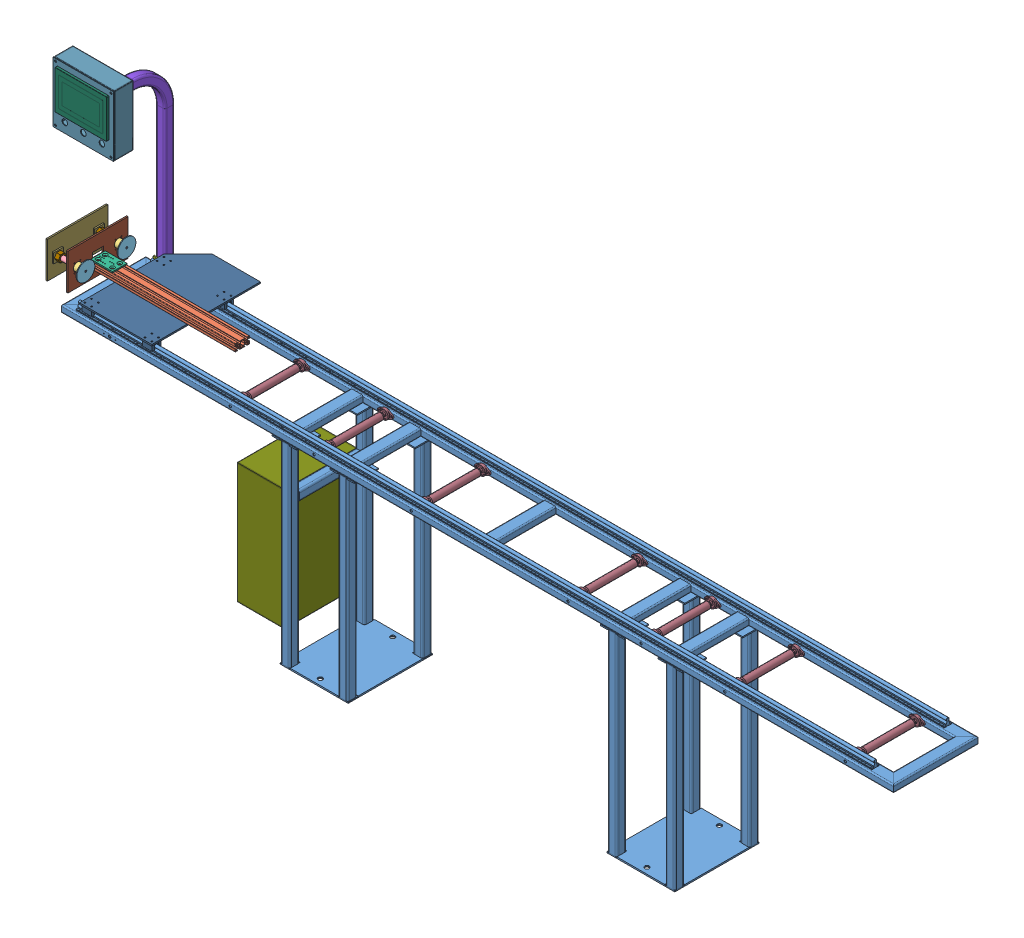
SolidWorks assembly machine-on, configuration Default. Lengths in mm.
Overall size (3563.76 1673.42 450).
29 component instances, 17 part files, 80 mates.
Components (placement in the parent):
- khung-1: khung [Default<As Machined>] at (964.4344 1502.6729 3549.2944) x (-1 0 0) z (0 0 1) size (3450 866.5 350)
- aluminium3060-600-1: aluminium3060-600 [Default<As Machined>] at (-185.5656 1577.1729 3549.2944) x (1 0 0) z (0 -1 0) size (600 60 30)
- LMH20UUx42-1: LMH20UUx42 [Default] at (-776.5656 1597.8953 3634.2944) size (42 54 38)
- LMH20UUx42-2: LMH20UUx42 [Default] at (-776.5656 1597.8953 3464.2944) size (42 54 38)
- truc)x-2: truc)x [Default] at (-752.3281 1597.8953 3634.2944) x (0 0.993547 -0.113425) z (0 0.113425 0.993547) size (20.5 122 21.25)
- chan3-1: chan3 [Default] at (-749.3281 1597.8953 3634.2944) x (0 0.828554 -0.559909) z (0 0.559909 0.828554) size (75 3 75)
- ga_bat-xilanhx80-1: ga_bat-xilanhx80 [Default] at (-738.5656 1592.1729 3549.2944) x (0 0 -1) z (1 0 0) size (60 5 90)
- v-50100-1: v-50100 [Default] at (-730.5656 1487.6729 3424.2944) x (0 0 -1) z (0 -1 0) size (55 100 50)
- gia-display-1: gia-display [Default<As Machined>] at (-705.5656 1428.6729 3349.2944) x (0 0 1) z (0 -1 0) size (276.08 230 916)
- v-50100-2: v-50100 [Default] at (-630.5656 1532.6729 3364.2944) x (-1 0 0) z (0 0 1) size (55 100 50)
- hex nut gradec_iso-1: hex nut gradec_iso [ISO - 4034 - M20 - N] at (-864.3281 1597.8953 3464.2944) x (0 -0.820442 -0.57173) z (-1 0 0) size (30 34.64 19)
- hex nut gradec_iso-2: hex nut gradec_iso [ISO - 4034 - M20 - N] at (-864.3281 1597.8953 3634.2944) x (0 1 0) z (-1 0 0) size (30 34.64 19)
- layout-table-2: layout-table [Default] at (-535.5656 1556.1729 3549.2944) size (300 31.9 450)
- chan_ban-2: chan_ban [Default] at (-789.5656 1597.6729 3549.2944) x (0 0 -1) z (0 -1 0) size (250 6 150)
- chan3-3: chan3 [Default] at (-749.3281 1597.8953 3464.2944) x (0 -0.419054 -0.907961) z (0 0.907961 -0.419054) size (75 3 75)
- truc)x-3: truc)x [Default] at (-752.3281 1597.8953 3464.2944) x (0 0.92615 0.377155) z (0 -0.377155 0.92615) size (20.5 122 21.25)
- chan2-2: chan2 [Default] at (-874.3281 1598.1153 3549.2944) x (0 0 1) z (0 1 0) size (250 12 150)
- pvc 200-2: pvc 200 [Default] at (-560.5656 1502.6729 3649.2944) x (0.546944 0.837169 0) z (-0.837169 0.546944 0) size (41.25 250 55.18)
- pvc 200-3: pvc 200 [Default] at (-60.5656 1502.6729 3449.2944) x (-0.546944 0.837169 0) z (0.837169 0.546944 0) size (41.25 250 55.18)
- pvc 200-4: pvc 200 [Default] at (286.4344 1502.6729 3449.2944) x (-0.546944 0.837169 0) z (0.837169 0.546944 0) size (41.25 250 55.18)
- pvc 200-5: pvc 200 [Default] at (689.4344 1502.6729 3449.2944) x (-0.546944 0.837169 0) z (0.837169 0.546944 0) size (41.25 250 55.18)
- pvc 200-6: pvc 200 [Default] at (1339.4344 1502.6729 3449.2944) x (-0.546944 0.837169 0) z (0.837169 0.546944 0) size (41.25 250 55.18)
- pvc 200-7: pvc 200 [Default] at (1642.4344 1502.6729 3449.2944) x (-0.546944 0.837169 0) z (0.837169 0.546944 0) size (41.25 250 55.18)
- pvc 200-8: pvc 200 [Default] at (1989.4344 1502.6729 3449.2944) x (0.546944 -0.837169 0) z (-0.837169 -0.546944 0) size (41.25 250 55.18)
- pvc 200-9: pvc 200 [Default] at (2489.4344 1502.6729 3449.2944) x (0.546944 -0.837169 0) z (-0.837169 -0.546944 0) size (41.25 250 55.18)
- Part2-1: Part2 [Default] at (-705.5656 2228.6729 3608.2944) x (0 -1 0) z (0 0 1) size (250.85 250.82 83.42)
- Delta DOP-107BV HMI-1: Delta DOP-107BV HMI [Varsayılan] at (-707.4156 2249.8229 3697.7944) x (1 0 0) z (0 0 -1) size (215 160.7 36.74)
- table electrical-1: table electrical [Default] at (143.4344 1045.6729 3554.2944) x (0 0 -1) z (0 1 0) size (300.76 200.75 500.76)
- door_table-1: door_table [Default] at (-50.0656 1046.1729 3553.0015) x (0 0 1) z (0 -1 0) size (237.66 7.33 448)
Mates (geometry in assembly coordinates):
- Coincident21: coincident aligned: circle of LMH20UUx42-1; cylinder of truc)x-2 through (-872.3544 1597.8953 3634.2944) axis (1 0 0) radius 10
- Coincident23: coincident anti-aligned: plane of truc)x-2 through (-750.3544 1597.8953 3634.2944) normal (1 0 0); plane of chan3-1 through (-750.3544 1597.8953 3634.2944) normal (-1 0 0)
- Concentric18: concentric anti-aligned: circle of truc)x-2; circle of chan3-1
- Coincident28: coincident anti-aligned: plane of aluminium3060-600-1 through (-785.5656 1592.1729 3559.9944) normal (0 1 0); plane of ga_bat-xilanhx80-1 through (-738.5656 1592.1729 3549.2944) normal (0 -1 0)
- Coincident29: coincident aligned: plane of aluminium3060-600-1 through (-785.5656 1590.1729 3519.2944) normal (0 0 -1); plane of ga_bat-xilanhx80-1 through (-738.5656 1597.1729 3519.2944) normal (0 0 -1)
- Coincident34: coincident anti-aligned: plane of khung-1 through (-735.5656 1487.6729 3419.0944) normal (0 -1 0); plane of v-50100-1 through (-630.5656 1487.6729 3424.2944) normal (0 1 0)
- Coincident35: coincident anti-aligned: plane of khung-1 through (-735.5656 1512.4729 3374.2944) normal (0 0 -1); plane of v-50100-1 through (-630.5656 1487.6729 3374.2944) normal (0 0 1)
- Distance4: distance = 30 mm aligned: plane of khung-1 through (-760.5656 1512.4729 3699.2944) normal (-1 0 0); plane of v-50100-1 through (-730.5656 1487.6729 3424.2944) normal (-1 0 0)
- Coincident37: coincident anti-aligned: plane of v-50100-1 through (-630.5656 1532.6729 3369.2944) normal (0 0 -1); plane of gia-display-1 through (-693.5656 2078.6729 3369.2944) normal (0 0 1)
- Distance6: distance = 60 mm aligned: plane of khung-1 through (-735.5656 1487.6729 3419.0944) normal (0 -1 0); plane of gia-display-1 through (-717.0656 1427.6729 3360.8754) normal (0 -1 0)
- Distance5: distance = 5 mm aligned: plane of gia-display-1 through (-725.5656 2078.6729 3337.2944) normal (-1 0 0); plane of v-50100-1 through (-730.5656 1487.6729 3424.2944) normal (-1 0 0)
- Coincident40: coincident anti-aligned: plane of gia-display-1 through (-685.5656 2078.6729 3361.2944) normal (1 0 0); plane of v-50100-2 through (-685.5656 1432.6729 3319.2944) normal (-1 0 0)
- Coincident42: coincident anti-aligned: plane of v-50100-1 through (-630.5656 1532.6729 3369.2944) normal (0 0 -1); plane of v-50100-2 through (-685.5656 1432.6729 3369.2944) normal (0 0 1)
- Coincident43: coincident aligned: plane of v-50100-1 through (-630.5656 1532.6729 3374.2944) normal (0 1 0); plane of v-50100-2 through (-630.5656 1532.6729 3364.2944) normal (0 1 0)
- Concentric22: concentric anti-aligned: cylinder of truc)x-2 through (-872.3544 1597.8953 3634.2944) axis (1 0 0) radius 10; cylinder of hex nut gradec_iso-2 through (-843.3544 1597.8953 3634.2944) axis (-1 0 0) radius 8.75
- Concentric23: concentric anti-aligned: cylinder of khung-1 through (2589.4344 1541.1729 3699.2944) axis (-1 0 0) radius 6; cylinder of layout-table-2 through (-678.0656 1541.1729 3699.2944) axis (1 0 0) radius 6
- Parallel4: parallel anti-aligned: plane of khung-1 through (-755.3656 1517.6729 3699.2944) normal (0 1 0); plane of layout-table-2 through (-535.5656 1556.1729 3549.2944) normal (0 -1 0)
- Coincident44: coincident anti-aligned: plane of aluminium3060-600-1 through (-785.5656 1562.1729 3538.5944) normal (0 -1 0); plane of layout-table-2 through (-535.5656 1562.1729 3549.2944) normal (0 1 0)
- Distance7: distance = 145 mm aligned: plane of aluminium3060-600-1 through (-785.5656 1564.1729 3579.2944) normal (0 0 1); plane of layout-table-2 through (-535.5656 1562.1729 3724.2944) normal (0 0 1)
- Distance8: distance = 200 mm aligned: plane of layout-table-2 through (-385.5656 1562.1729 3549.2944) normal (1 0 0); plane of aluminium3060-600-1 through (-185.5656 1590.1729 3521.2944) normal (1 0 0)
- Coincident47: coincident anti-aligned: plane of aluminium3060-600-1 through (-785.5656 1590.1729 3521.2944) normal (-1 0 0); plane of chan_ban-2 through (-785.5656 1597.6729 3549.2944) normal (1 0 0)
- Concentric24: concentric anti-aligned: circle of aluminium3060-600-1; circle of chan_ban-2
- Coincident49: coincident anti-aligned: plane of ga_bat-xilanhx80-1 through (-783.5656 1597.1729 3549.2944) normal (-1 0 0); plane of chan_ban-2 through (-783.5656 1597.6729 3549.2944) normal (1 0 0)
- Concentric25: concentric anti-aligned: cylinder of LMH20UUx42-1 through (-826.5656 1597.8953 3634.2944) axis (-1 0 0) radius 16; cylinder of chan_ban-2 through (-812.5656 1597.8953 3634.2944) axis (1 0 0) radius 17
- Coincident50: coincident anti-aligned: plane of LMH20UUx42-1 through (-789.5656 1597.8953 3634.2944) normal (1 0 0); plane of chan_ban-2 through (-789.5656 1597.6729 3549.2944) normal (-1 0 0)
- Parallel5: parallel aligned: plane of LMH20UUx42-1 through (-789.5656 1617.0786 3653.2944) normal (0 0 1); plane of chan_ban-2 through (-783.5656 1597.6729 3674.2944) normal (0 0 1)
- Concentric26: concentric anti-aligned: cylinder of LMH20UUx42-2 through (-826.5656 1597.8953 3464.2944) axis (-1 0 0) radius 16; cylinder of chan_ban-2 through (-812.5656 1597.8953 3464.2944) axis (1 0 0) radius 17
- Parallel6: parallel anti-aligned: plane of LMH20UUx42-2 through (-789.5656 1617.0786 3483.2944) normal (0 0 1); plane of chan_ban-2 through (-783.5656 1597.6729 3424.2944) normal (0 0 -1)
- Coincident53: coincident anti-aligned: plane of LMH20UUx42-2 through (-789.5656 1597.8953 3464.2944) normal (1 0 0); plane of chan_ban-2 through (-789.5656 1597.6729 3549.2944) normal (-1 0 0)
- Parallel7: parallel aligned: plane of aluminium3060-600-1 through (-785.5656 1592.1729 3529.9944) normal (0 1 0); plane of chan_ban-2 through (-783.5656 1672.6729 3549.2944) normal (0 1 0)
- LimitDistance1: limit distance = 50 mm anti-aligned: plane of LMH20UUx42-1 through (-755.5656 1612.8453 3634.2944) normal (1 0 0); plane of chan3-1 through (-752.3281 1597.8953 3634.2944) normal (-1 0 0)
- Concentric27: concentric anti-aligned: circle of chan3-3; circle of truc)x-3
- Coincident56: coincident anti-aligned: plane of chan3-3 through (-750.3544 1597.8953 3464.2944) normal (-1 0 0); plane of truc)x-3 through (-750.3544 1597.8953 3464.2944) normal (1 0 0)
- Concentric28: concentric aligned: cylinder of LMH20UUx42-2 through (-797.5656 1597.8953 3464.2944) axis (1 0 0) radius 10; cylinder of truc)x-3 through (-872.3544 1597.8953 3464.2944) axis (1 0 0) radius 10
- LimitDistance3: limit distance = 50 mm anti-aligned: plane of chan3-3 through (-752.3281 1597.8953 3464.2944) normal (-1 0 0); plane of LMH20UUx42-2 through (-755.5656 1612.8453 3464.2944) normal (1 0 0)
- Coincident58: coincident aligned: plane of chan3-1 through (-747.3544 1597.8953 3634.2944) normal (1 0 0); plane of chan3-3 through (-747.3544 1597.8953 3464.2944) normal (1 0 0)
- LimitDistance4: limit distance = 0 mm anti-aligned: plane of layout-table-2 through (-685.5656 1562.1729 3549.2944) normal (-1 0 0); plane of gia-display-1 through (-685.5656 2078.6729 3361.2944) normal (1 0 0)
- Concentric29: concentric anti-aligned: cylinder of hex nut gradec_iso-1 through (-843.3544 1597.8953 3464.2944) axis (-1 0 0) radius 8.75; cylinder of truc)x-3 through (-872.3544 1597.8953 3464.2944) axis (1 0 0) radius 10
- Distance14: distance = 10 mm aligned: plane of hex nut gradec_iso-1 through (-864.3281 1587.9926 3478.5049) normal (-1 0 0); plane of truc)x-3 through (-874.3281 1597.8953 3464.2944) normal (-1 0 0)
- Concentric30: concentric anti-aligned: cylinder of truc)x-2 through (-872.3544 1597.8953 3634.2944) axis (1 0 0) radius 10; cylinder of hex nut gradec_iso-2 through (-843.3544 1597.8953 3634.2944) axis (-1 0 0) radius 8.75
- Coincident63: coincident aligned: plane of hex nut gradec_iso-1 through (-862.3544 1587.9926 3478.5049) normal (-1 0 0); plane of hex nut gradec_iso-2 through (-862.3544 1597.8953 3616.9739) normal (-1 0 0)
- Concentric31: concentric anti-aligned: cylinder of truc)x-3 through (-872.3544 1597.8953 3464.2944) axis (1 0 0) radius 10; cylinder of chan2-2 through (-860.3544 1597.8953 3464.2944) axis (-1 0 0) radius 8.75
- Parallel10: parallel aligned: plane of chan_ban-2 through (-783.5656 1672.6729 3549.2944) normal (0 1 0); plane of chan2-2 through (-866.3544 1673.1153 3549.2944) normal (0 1 0)
- Coincident65: coincident aligned: plane of truc)x-2 through (-872.3544 1597.8953 3634.2944) normal (-1 0 0); plane of chan2-2 through (-872.3544 1598.1153 3549.2944) normal (-1 0 0)
- Coincident67: coincident anti-aligned: plane of khung-1 through (-735.5656 1492.8729 3424.2944) normal (0 0 1); plane of pvc 200-2 through (-560.5656 1502.6729 3424.2944) normal (0 0 -1)
- Concentric34: concentric anti-aligned: circle of khung-1; circle of pvc 200-2
- Coincident68: coincident anti-aligned: plane of khung-1 through (2664.4344 1492.8729 3674.2944) normal (0 0 -1); plane of pvc 200-3 through (-60.5656 1502.6729 3674.2944) normal (0 0 1)
- Concentric35: concentric anti-aligned: circle of khung-1; circle of pvc 200-3
- Concentric36: concentric anti-aligned: cylinder of khung-1 through (286.4344 1502.6729 3724.2944) axis (0 0 -1) radius 5; cylinder of pvc 200-4 through (286.4344 1502.6729 3658.2944) axis (0 0 1) radius 6
- Coincident69: coincident anti-aligned: plane of khung-1 through (2664.4344 1492.8729 3674.2944) normal (0 0 -1); plane of pvc 200-4 through (286.4344 1502.6729 3674.2944) normal (0 0 1)
- Coincident70: coincident anti-aligned: plane of khung-1 through (2664.4344 1492.8729 3674.2944) normal (0 0 -1); plane of pvc 200-5 through (689.4344 1502.6729 3674.2944) normal (0 0 1)
- Concentric37: concentric anti-aligned: circle of khung-1; circle of pvc 200-5
- Coincident71: coincident anti-aligned: plane of khung-1 through (2664.4344 1492.8729 3674.2944) normal (0 0 -1); plane of pvc 200-6 through (1339.4344 1502.6729 3674.2944) normal (0 0 1)
- Concentric38: concentric anti-aligned: circle of khung-1; circle of pvc 200-6
- Concentric39: concentric anti-aligned: circle of khung-1; circle of pvc 200-7
- Coincident72: coincident anti-aligned: plane of khung-1 through (2664.4344 1492.8729 3674.2944) normal (0 0 -1); plane of pvc 200-7 through (1642.4344 1502.6729 3674.2944) normal (0 0 1)
- Coincident73: coincident anti-aligned: plane of khung-1 through (2664.4344 1492.8729 3674.2944) normal (0 0 -1); plane of pvc 200-8 through (1989.4344 1502.6729 3674.2944) normal (0 0 1)
- Concentric40: concentric aligned: circle of khung-1; circle of pvc 200-8
- Coincident74: coincident anti-aligned: plane of khung-1 through (2664.4344 1492.8729 3674.2944) normal (0 0 -1); plane of pvc 200-9 through (2489.4344 1502.6729 3674.2944) normal (0 0 1)
- Concentric41: concentric anti-aligned: circle of khung-1; circle of pvc 200-9
- Concentric42: concentric aligned: circle of khung-1; circle of pvc 200-2
- Parallel11: parallel aligned: plane of pvc 200-2 through (-551.4615 1519.3496 3429.7944) normal (0.479167 0.877724 0); plane of pvc 200-3 through (-51.4615 1519.3496 3429.7944) normal (0.479167 0.877724 0)
- Parallel12: parallel aligned: plane of pvc 200-3 through (-51.4615 1519.3496 3429.7944) normal (0.479167 0.877724 0); plane of pvc 200-4 through (295.5385 1519.3496 3429.7944) normal (0.479167 0.877724 0)
- Parallel13: parallel aligned: plane of pvc 200-4 through (295.5385 1519.3496 3429.7944) normal (0.479167 0.877724 0); plane of pvc 200-5 through (698.5385 1519.3496 3429.7944) normal (0.479167 0.877724 0)
- Parallel14: parallel aligned: plane of pvc 200-5 through (698.5385 1519.3496 3429.7944) normal (0.479167 0.877724 0); plane of pvc 200-6 through (1348.5385 1519.3496 3429.7944) normal (0.479167 0.877724 0)
- Parallel15: parallel aligned: plane of pvc 200-6 through (1348.5385 1519.3496 3429.7944) normal (0.479167 0.877724 0); plane of pvc 200-7 through (1651.5385 1519.3496 3429.7944) normal (0.479167 0.877724 0)
- Parallel16: parallel aligned: plane of pvc 200-7 through (1651.5385 1519.3496 3429.7944) normal (0.479167 0.877724 0); plane of pvc 200-8 through (1998.5385 1519.3496 3429.7944) normal (0.479167 0.877724 0)
- Parallel17: parallel aligned: plane of pvc 200-8 through (1998.5385 1519.3496 3429.7944) normal (0.479167 0.877724 0); plane of pvc 200-9 through (2498.5385 1519.3496 3429.7944) normal (0.479167 0.877724 0)
- Coincident92: coincident anti-aligned: plane of gia-display-1 through (-805.5656 2328.6729 3605.2944) normal (0 0 1); plane of Part2-1 through (-705.5656 2228.6729 3605.2944) normal (0 0 -1)
- Coincident93: coincident anti-aligned: plane of Part2-1 through (-705.5656 2228.6729 3688.2944) normal (0 0 1); plane of Delta DOP-107BV HMI-1 through (-707.4156 2249.8229 3688.2944) normal (0 0 -1)
- Coincident94: coincident anti-aligned: plane of Part2-1 through (-805.5656 2178.6729 3688.2944) normal (0 1 0); plane of Delta DOP-107BV HMI-1 through (-805.5656 2178.6729 3661.0544) normal (0 -1 0)
- Coincident95: coincident anti-aligned: plane of Part2-1 through (-805.5656 2178.6729 3688.2944) normal (1 0 0); plane of Delta DOP-107BV HMI-1 through (-805.5656 2178.6729 3661.0544) normal (-1 0 0)
- Concentric43: concentric anti-aligned: circle of gia-display-1; circle of Part2-1
- Concentric44: concentric anti-aligned: circle of gia-display-1; circle of Part2-1
- Distance15: distance = 192 mm anti-aligned: plane of khung-1 through (2664.4344 1487.6729 3679.4944) normal (0 -1 0); plane of table electrical-1 through (143.4344 1295.6729 3554.2944) normal (0 1 0)
- Coincident97: coincident anti-aligned: plane of khung-1 through (146.4344 1484.6729 3692.2944) normal (-1 0 0); plane of table electrical-1 through (146.4344 1045.6729 3554.2944) normal (1 0 0)
- Distance16: distance = 30 mm aligned: plane of khung-1 through (154.4344 1484.6729 3374.2944) normal (0 0 -1); plane of table electrical-1 through (143.4344 1045.6729 3404.2944) normal (0 0 -1)
- Concentric45: concentric anti-aligned: cylinder of table electrical-1 through (-46.0656 1275.6729 3442.5015) axis (0 -1 0) radius 2.5; cylinder of door_table-1 through (-46.0656 821.6729 3442.5015) axis (0 1 0) radius 1.5
- Distance17: distance = 2 mm anti-aligned: plane of door_table-1 through (-50.0656 827.6729 3553.0015) normal (0 -1 0); plane of table electrical-1 through (143.4344 825.6729 3554.2944) normal (0 1 0)
- LimitAngle1: limit planar angle = 0 rad anti-aligned: plane of table electrical-1 through (-41.5656 1045.6729 3554.2944) normal (-1 0 0); plane of door_table-1 through (-47.0656 1046.1729 3553.0015) normal (1 0 0)
